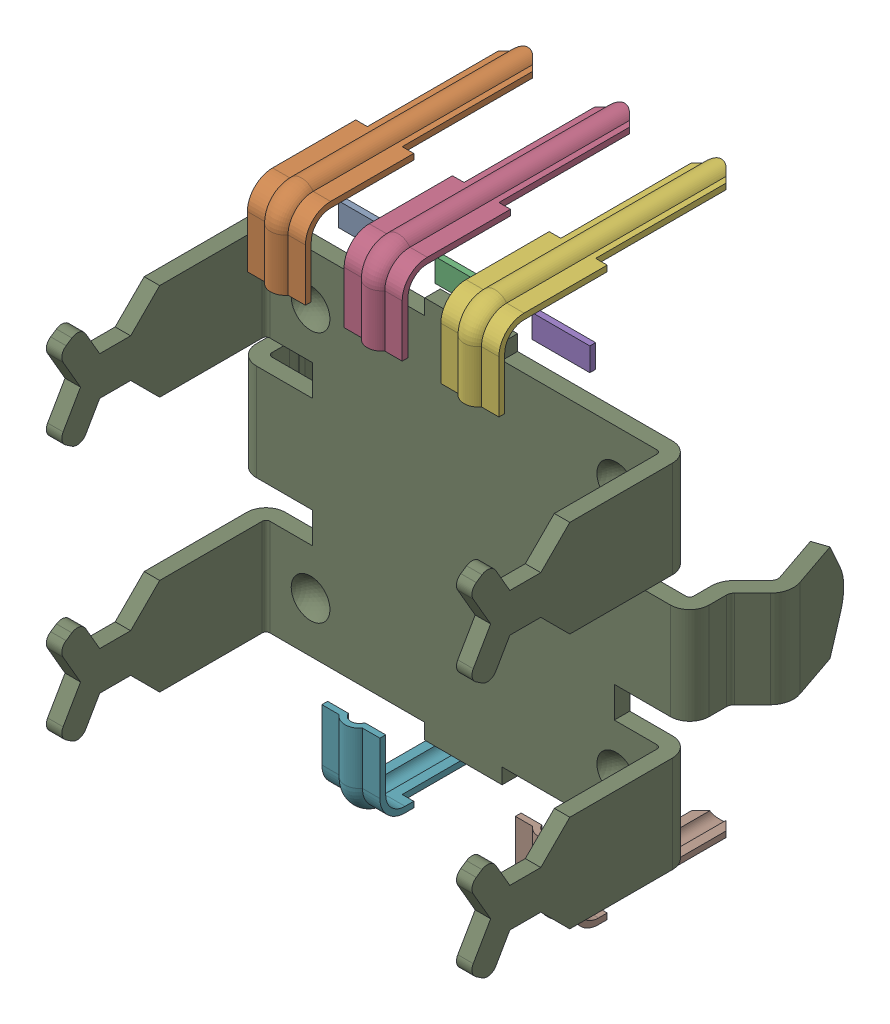
SolidWorks assembly User Library-EC11B15244_Pins, configuration Default. Lengths in mm.
Overall size (13.1 14.95 9.45).
6 component instances, 3 part files, 0 mates.
Components (placement in the parent):
- User Library-EC11B15244_Imported-1: User Library-EC11B15244_Imported [Default] at (-2.5 7.575 -10.2243) x (0 -1 0) z (0 0 1) size (2.34 1.5 6.65)
- User Library-EC11B15244_Imported-2: User Library-EC11B15244_Imported [Default] at (0 7.575 -10.2243) x (0 -1 0) z (0 0 1) size (2.34 1.5 6.65)
- User Library-EC11B15244_Imported-3: User Library-EC11B15244_Imported [Default] at (2.5 7.575 -10.2243) x (0 -1 0) z (0 0 1) size (2.34 1.5 6.65)
- User Library-EC11B15244_Pin-1: User Library-EC11B15244_Pin [Default] at (-2.5 -7.075 -10.2243) x (0 1 0) z (0 0 1) size (2.15 1.5 4.73)
- User Library-EC11B15244_Pin-2: User Library-EC11B15244_Pin [Default] at (2.5 -7.075 -10.2243) x (0 1 0) z (0 0 1) size (2.15 1.5 4.73)
- User Library-EC11B15244_Sheet Metal Part53-1: User Library-EC11B15244_Sheet Metal Part53 [Default] at (-24.7094 3.8245 8.4125) size (13.1 9.9 9.18)
